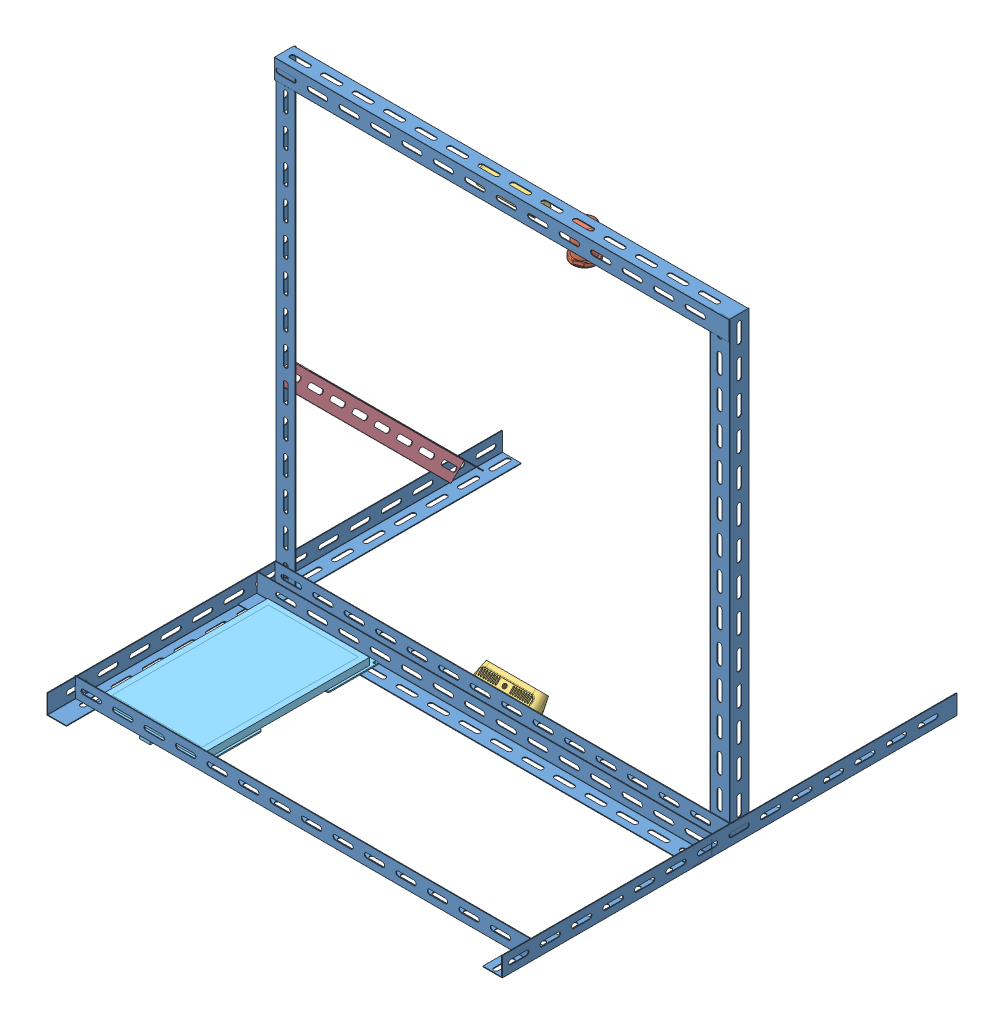
SolidWorks assembly FYBmyson, configuration 默认. Lengths in mm.
Overall size (651 657.04 650).
16 component instances, 5 part files, 43 mates.
Components (placement in the parent):
- 框架-1: 框架 [默认] at (-496.9473 5.3341 1008.2186) size (650 28 28)
- 框架-2: 框架 [默认] at (153.0527 5.3341 1044.7814) x (-1 0 0) z (0 0 -1) size (650 28 28)
- 框架-3: 框架 [默认] at (-496.9473 6.3341 1045.7814) x (0 1 0) z (0 0 -1) size (650 28 28) (hidden)
- 框架-4: 框架 [默认] at (-491.1659 6.3341 1013) x (0 1 0) z (-1 0 0) size (650 28 28)
- 框架-5: 框架 [默认] at (-497.9473 5.3341 1293.2186) size (650 28 28)
- 框架-6: 框架 [默认] at (152.0527 656.3341 1045.7814) x (0 -1 0) z (0 0 -1) size (650 28 28) (hidden)
- 框架-7: 框架 [默认] at (-497.9473 650.5527 1014) x (1 0 0) z (0 1 0) size (650 28 28)
- 框架-8: 框架 [默认] at (-492.1659 4.3341 688.9545) x (0 0 1) z (-1 0 0) size (650 28 28)
- 框架-9: 框架 [默认] at (146.2714 656.3341 1013) x (0 -1 0) z (1 0 0) size (650 28 28)
- 框架-10: 框架 [默认] at (147.2714 4.3341 1338.9545) x (0 0 -1) z (1 0 0) size (650 28 28)
- mic-2: mic [默认] at (-73.0593 610.3341 995) x (0.388605 0 0.921405) z (-0.921405 0 0.388605) size (36 45 36)
- RealSense_D435-1: RealSense_D435 [Default] at (-176.102 648.4661 1001.9914) x (-1 0 0) z (0 -0.707107 -0.707107) size (90.75 24.75 24.23)
- RealSense_D435-2: RealSense_D435 [Default] at (-183.0919 11.8176 998.2569) x (1 0 0) z (0 0.707107 -0.707107) size (90.75 24.75 24.23)
- 框架2-1: 框架2 [默认] at (-490.1659 272.6204 992.201) x (0 -0.707107 -0.707107) z (-1 0 0) size (350 28 28) (hidden)
- 框架2-2: 框架2 [默认] at (145.2714 25.1331 744.7136) x (0 0.707107 0.707107) z (1 0 0) size (350 28 28) (hidden)
- 10'1-1: 10'1 [默认] at (-398.0511 6.3341 1169) x (0 0 -1) z (1 0 0) size (258 17.75 152)
Mates (geometry in assembly coordinates):
- 距离1: distance = 25 mm anti-aligned: plane of 框架-1 through (153.0527 5.6341 1014) normal (0 0 1); plane of 框架-2 through (-496.9473 5.6341 1039) normal (0 0 -1)
- 重合2: coincident aligned: plane of 框架-1 through (153.0527 5.3341 1008.2186) normal (0 -1 0); plane of 框架-2 through (-496.9473 5.3341 1044.7814) normal (0 -1 0)
- 重合3: coincident aligned: plane of 框架-1 through (153.0527 5.6341 986.3) normal (1 0 0); plane of 框架-2 through (153.0527 5.6341 1066.7) normal (1 0 0)
- 重合4: coincident anti-aligned: plane of 框架-2 through (-496.9473 5.3341 1044.7814) normal (0 -1 0); plane of 框架-10 through (151.7527 5.3341 688.9545) normal (0 1 0)
- 重合6: coincident anti-aligned: plane of 框架-1 through (-496.9473 5.6341 986.3) normal (-1 0 0); plane of 框架-8 through (-496.9473 5.6341 1338.9545) normal (1 0 0)
- 重合7: coincident anti-aligned: plane of 框架-2 through (-496.9473 5.3341 1044.7814) normal (0 -1 0); plane of 框架-8 through (-496.6473 5.3341 1338.9545) normal (0 1 0)
- 重合8: coincident aligned: plane of 框架-8 through (-470.2473 4.6341 688.9545) normal (0 0 -1); plane of 框架-10 through (125.3527 4.6341 688.9545) normal (0 0 -1)
- 重合9: coincident anti-aligned: plane of 框架-9 through (152.0527 6.3341 1012.7) normal (1 0 0); plane of 框架-10 through (152.0527 5.6341 688.9545) normal (-1 0 0)
- 重合10: coincident anti-aligned: plane of 框架-1 through (153.0527 6.6341 1013) normal (0 0 -1); plane of 框架-9 through (146.2714 6.3341 1013) normal (0 0 1)
- 重合11: coincident anti-aligned: plane of 框架-1 through (153.0527 6.3341 1012.7) normal (0 1 0); plane of 框架-9 through (124.3527 6.3341 1012.7) normal (0 -1 0)
- 重合12: coincident anti-aligned: plane of 框架-2 through (-496.9473 6.3341 1040.3) normal (0 1 0); plane of 框架-6 through (151.7527 6.3341 1067.7) normal (0 -1 0)
- 重合13: coincident anti-aligned: plane of 框架-2 through (-496.9473 6.6341 1040) normal (0 0 1); plane of 框架-6 through (151.7527 6.3341 1040) normal (0 0 -1)
- 重合14: coincident anti-aligned: plane of 框架-6 through (152.0527 6.3341 1045.7814) normal (1 0 0); plane of 框架-10 through (152.0527 5.6341 688.9545) normal (-1 0 0)
- 重合15: coincident aligned: plane of 框架-3 through (-496.6473 6.3341 1067.7) normal (0 -1 0); plane of 框架-4 through (-469.2473 6.3341 1012.7) normal (0 -1 0)
- 重合16: coincident anti-aligned: plane of 框架-2 through (-496.9473 6.3341 1040.3) normal (0 1 0); plane of 框架-3 through (-496.6473 6.3341 1067.7) normal (0 -1 0)
- 重合17: coincident anti-aligned: plane of 框架-3 through (-496.9473 656.3341 1045.7814) normal (-1 0 0); plane of 框架-8 through (-496.9473 5.6341 1338.9545) normal (1 0 0)
- 重合18: coincident anti-aligned: plane of 框架-2 through (-496.9473 6.6341 1040) normal (0 0 1); plane of 框架-3 through (-496.6473 656.3341 1040) normal (0 0 -1)
- 重合19: coincident anti-aligned: plane of 框架-4 through (-496.9473 656.3341 1012.7) normal (-1 0 0); plane of 框架-8 through (-496.9473 5.6341 1338.9545) normal (1 0 0)
- 重合20: coincident anti-aligned: plane of 框架-1 through (153.0527 6.6341 1013) normal (0 0 -1); plane of 框架-4 through (-491.1659 656.3341 1013) normal (0 0 1)
- 重合21: coincident anti-aligned: plane of 框架-7 through (152.0527 655.0341 1013) normal (0 0 -1); plane of 框架-9 through (146.2714 6.3341 1013) normal (0 0 1)
- 重合22: coincident aligned: plane of 框架-7 through (152.0527 628.6341 1013.7) normal (1 0 0); plane of 框架-9 through (152.0527 6.3341 1012.7) normal (1 0 0)
- 重合23: coincident aligned: plane of 框架-7 through (152.0527 656.3341 1013.7) normal (0 1 0); plane of 框架-9 through (124.3527 656.3341 1012.7) normal (0 1 0)
- 重合24: coincident anti-aligned: plane of 框架-5 through (152.0527 5.6341 1271.3) normal (1 0 0); plane of 框架-10 through (152.0527 5.6341 688.9545) normal (-1 0 0)
- 重合25: coincident aligned: plane of 框架-2 through (-496.9473 5.3341 1044.7814) normal (0 -1 0); plane of 框架-5 through (152.0527 5.3341 1293.2186) normal (0 -1 0)
- 重合27: coincident aligned: plane of 框架-2 through (153.0527 5.6341 1066.7) normal (1 0 0); plane of 框架-10 through (153.0527 4.6341 688.9545) normal (1 0 0)
- 角度1: planar angle = 0.785398 rad anti-aligned: plane of RealSense_D435-2 through (-183.0919 11.8176 998.2569) normal (0 -0.707107 0.707107); plane of 框架-1 through (153.0527 6.3341 1012.7) normal (0 1 0)
- 平行4: parallel aligned: cylinder of 框架-1 through (153.0527 6.0341 986.3) axis (-1 0 0) radius 0.3; line of RealSense_D435-2 through (-147.7131 24.015 1003.4177) axis (-1 0 0)
- 重合32: coincident aligned: line of 框架-1 through (153.0527 6.3341 986.3) axis (-1 0 0); line of RealSense_D435-2 through (-147.655 6.3341 986.3) axis (-1 0 0)
- 重合36: coincident anti-aligned: plane of 框架-7 through (152.0527 655.3341 1012.7) normal (0 -1 0); plane of fyb-2 through (-73.0593 655.3341 995) normal (0 1 0)
- 重合38: coincident anti-aligned: plane of 框架-9 through (151.0527 6.3341 1011.7) normal (-1 0 0); plane of 框架2-2 through (151.0527 272.4083 992.4131) normal (1 0 0)
- 角度2: planar angle = 0.785398 rad anti-aligned: plane of 框架2-2 through (150.3527 252.8215 1012) normal (0 -0.707107 0.707107); plane of 框架-9 through (150.7527 6.3341 1012) normal (0 0 -1)
- 重合40: coincident: plane of 框架-10 through (151.7527 5.3341 688.9545) normal (0 1 0); line of 框架2-2 through (150.3527 5.3341 764.5126) axis (1 0 0)
- 重合46: coincident: plane of 框架-9 through (150.7527 6.3341 1012) normal (0 0 -1); line of 框架2-2 through (150.3527 252.8215 1012) axis (1 0 0)
- 重合47: coincident aligned: plane of 框架2-1 through (-490.1659 25.1331 744.7136) normal (0 0.707107 -0.707107); plane of 框架2-2 through (145.2714 272.6204 992.201) normal (0 0.707107 -0.707107)
- 重合48: coincident anti-aligned: plane of 框架-4 through (-495.9473 656.3341 1011.7) normal (1 0 0); plane of 框架2-1 through (-495.9473 24.9209 744.9258) normal (-1 0 0)
- 重合49: coincident aligned: plane of 框架2-1 through (-468.2473 24.9209 744.9258) normal (0 -0.707107 -0.707107); plane of 框架2-2 through (123.3527 24.9209 744.9258) normal (0 -0.707107 -0.707107)
- 重合50: coincident: plane of 框架-2 through (-496.9473 6.6341 1040) normal (0 0 1); line of 10'1-1 through (-325.0511 7.9841 1040) axis (-1 0 0)
- 重合51: coincident anti-aligned: plane of 框架-2 through (-496.9473 6.3341 1040.3) normal (0 1 0); plane of 10'1-1 through (-398.0511 6.3341 1169) normal (0 -1 0)
- 重合52: coincident anti-aligned: plane of 框架-5 through (152.0527 6.6341 1298) normal (0 0 -1); plane of 10'1-1 through (-474.0511 7.9841 1298) normal (0 0 1)
- 锁定7: lock: unknown of 框架-1; unknown of 框架-10
- 相切4: tangent: plane of 框架-7 through (152.0527 655.0341 1013) normal (0 0 -1); circle of fyb-2
- 角度6: planar angle = 0.785398 rad aligned: plane of RealSense_D435-1 through (-176.102 632.2027 985.7279) normal (0 -0.707107 -0.707107); plane of 框架-7 through (152.0527 655.3341 1012.7) normal (0 -1 0)
- 平行9: parallel anti-aligned: line of 框架-7 through (152.0527 628.3341 1013.7) axis (-1 0 0); line of RealSense_D435-1 through (-211.539 642.5447 1007.9128) axis (1 0 0)
